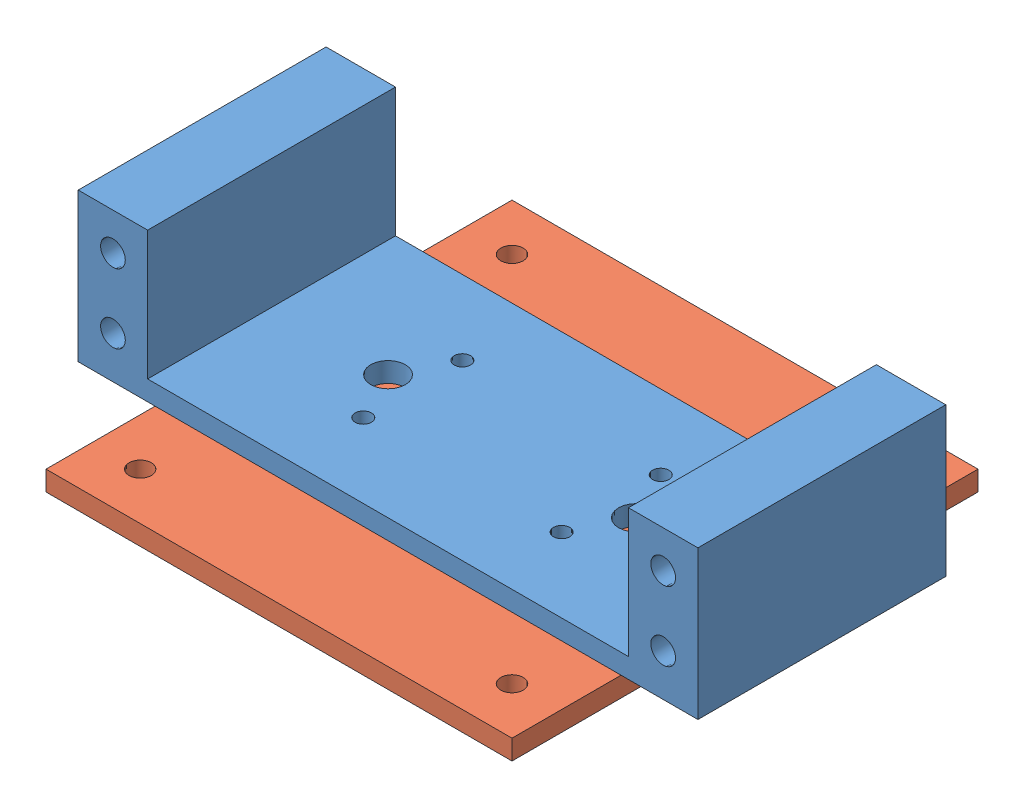
SolidWorks assembly mount_gripper_assembly, configuration Default. Lengths in mm.
Overall size (125 36 94).
3 component instances, 3 part files, 7 mates.
Components (placement in the parent):
- mount_gripper_UR5-1: mount_gripper_UR5 [Default] at (62.5 0 -25) x (0 0 1) z (1 0 0) (suppressed, hidden)
- mount_gripper-2: mount_gripper [Default] at origin size (125 32 50)
- mount_gripper_monitorarm-1: mount_gripper_monitorarm [Default] at (23.5 -4 -2.5) x (1 0 0) z (0 1 0) size (94 94 4)
Mates (geometry in assembly coordinates):
- Coincident3: coordinate: point of mount_gripper-2
- Concentric5: concentric anti-aligned: cylinder of mount_gripper_UR5-1 through (82.5 -4 -15) axis (0 1 0) radius 1.65; axis of mount_gripper-2 through (82.5 4 -15) axis (0 -1 0)
- Concentric6: concentric anti-aligned: cylinder of mount_gripper_UR5-1 through (42.5 -4 -35) axis (0 1 0) radius 1.65; cylinder of mount_gripper-2 through (42.5 30 -35) axis (0 -1 0) radius 1.65
- Coincident4: coincident anti-aligned: plane of mount_gripper_UR5-1 through (62.5 0 -25) normal (0 1 0); plane of mount_gripper-2 through (0 0 0) normal (0 -1 0)
- Concentric7: concentric aligned: cylinder of mount_gripper-2 through (82.5 32 -35) axis (0 -1 0) radius 1.65; cylinder of mount_gripper_monitorarm-1 through (82.5 0 -35) axis (0 -1 0) radius 1.65
- Concentric8: concentric aligned: cylinder of mount_gripper-2 through (42.5 32 -35) axis (0 -1 0) radius 1.65; cylinder of mount_gripper_monitorarm-1 through (42.5 0 -35) axis (0 -1 0) radius 1.65
- Coincident5: coincident anti-aligned: plane of mount_gripper-2 through (0 0 0) normal (0 -1 0); plane of mount_gripper_monitorarm-1 through (23.5 0 -2.5) normal (0 1 0)
